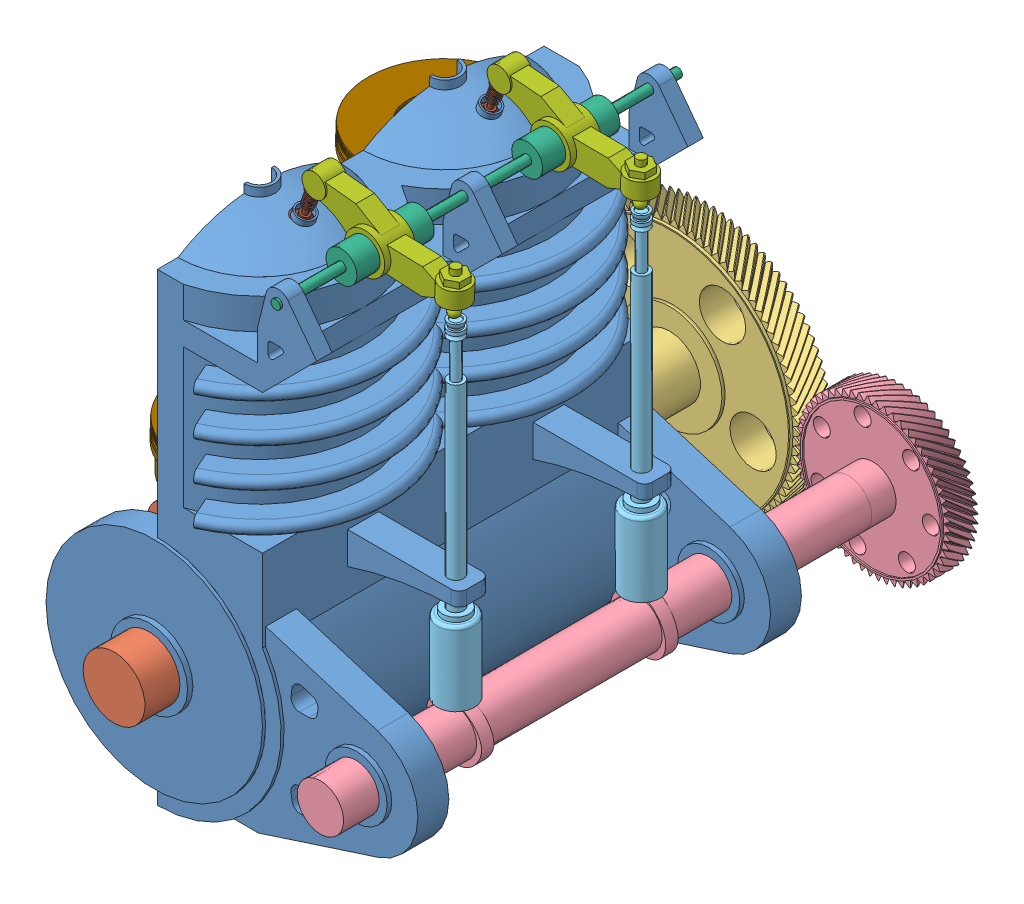
SolidWorks assembly Assem2, configuration Default. Lengths in mm.
Overall size (28.3 38.4 39.92).
18 component instances, 11 part files, 39 mates.
Components (placement in the parent):
- Two Cylinder Engine 1.Engine Block-1: Two Cylinder Engine 1.Engine Block [Default] at (0.0149 -0.0207 20.7725) size (23.65 32.82 28.05)
- Two Cylinder Engine 6...Crankshaft-1: Two Cylinder Engine 6...Crankshaft [Default] at (0.0149 7.9793 36.3725) x (-0.999999 0.00138 0) z (0 0 1) size (8.94 13 15.46)
- Two Cylinder Engine 6...Crankshaft-3: Two Cylinder Engine 6...Crankshaft [Default] at (0.0149 7.9793 29.8525) x (-0.999999 0.00138 0) z (0 0 -1) size (8.94 13 15.46)
- Two Cylinder Engine 8.Crankshaft Sprocket-1: Two Cylinder Engine 8.Crankshaft Sprocket [Default] at (0.0149 7.9793 12.6525) x (-0.999999 0.00138 0) z (0 0 1) size (16.49 16.5 9)
- Two Cylinder Engine 9.Camshaft with Sprocket-1: Two Cylinder Engine 9.Camshaft with Sprocket [Default] at (12.9589 7.5368 12.4525) x (-0.752432 0.65867 0) z (0 0 -1) size (10.07 10.06 38.02)
- Two Cylinder Engine 5..Pushrod-1: Two Cylinder Engine 5..Pushrod [Default] at (12.8149 13.9674 39.2725) x (-0.679929 0 -0.733278) z (0 1 0) size (2.4 2.4 21.18)
- Two Cylinder Engine 5..Pushrod-2: Two Cylinder Engine 5..Pushrod [Default] at (12.8149 14.0739 27.2725) x (0.936074 0 -0.351803) z (0 1 0) size (2.4 2.4 21.18)
- Two Cylinder Engine 10.Arbor-1: Two Cylinder Engine 10.Arbor [Default] at (7.8149 31.9993 45.9225) x (-0.655287 0.75538 0) z (0 0 -1) size (2 2 26)
- Two Cylinder Engine 7..Rocker Arm-1: Two Cylinder Engine 7..Rocker Arm [Default] at (7.8149 31.9993 39.1695) x (-0.800775 0.598966 0) z (0 0 -1) size (9.73 5.52 2)
- Two Cylinder Engine 7..Rocker Arm-2: Two Cylinder Engine 7..Rocker Arm [Default] at (7.8149 31.9993 27.1625) x (-0.813863 0.581056 0) z (0 0 -1) size (9.73 5.52 2)
- Two Cylinder Engine 4..Connecting Rod-1: Two Cylinder Engine 4..Connecting Rod [Default] at (0.0076 2.7203 39.1725) x (1 -0.00053 0) z (0 0 1) size (3.5 16.84 4)
- Two Cylinder Engine 4..Connecting Rod-2: Two Cylinder Engine 4..Connecting Rod [Default] at (0.0221 13.2383 27.0525) x (1 0.00053 0) z (0 0 1) size (3.5 16.84 4)
- Two Cylinder Engine 2.Pistonn-1: Two Cylinder Engine 2.Pistonn [Default] at (0.0149 15.5038 39.1825) x (0 0 1) z (-1 0 0) size (10 2.97 10)
- Two Cylinder Engine 3.Pin-1: Two Cylinder Engine 3.Pin [Default] at (0.0149 16.4103 34.4325) x (0.939236 0.343271 0) z (0 0 1) size (1.6 1.6 9.5)
- Two Cylinder Engine 2.Pistonn-2: Two Cylinder Engine 2.Pistonn [Default] at (0.0149 26.0218 27.1825) x (0 0 1) z (-1 0 0) size (10 2.97 10)
- Two Cylinder Engine 3.Pin-2: Two Cylinder Engine 3.Pin [Default] at (0.0149 26.9283 22.4325) x (0.999854 0.017111 0) z (0 0 1) size (1.6 1.6 9.5)
- Two Cylinder Engine 11.Valve-1: Two Cylinder Engine 11.Valve [Default] at (2.7613 30.7736 39.1825) x (0.939693 -0.34202 0) z (0 0 1) size (2.2 2.69 2.2)
- Two Cylinder Engine 11.Valve-2: Two Cylinder Engine 11.Valve [Default] at (2.7309 30.6901 27.1825) x (0.939693 -0.34202 0) z (0 0 1) size (2.2 2.69 2.2)
Mates (geometry in assembly coordinates):
- Concentric1: concentric: cylinder of Two Cylinder Engine 1.Engine Block-1 through (0.0149 7.9793 46.3125) axis (0 0 -1) radius 2; cylinder of Two Cylinder Engine 6...Crankshaft-1 through (0.0149 7.9793 45.2325) axis (0 0 -1) radius 2
- Distance1: distance = 2.6 mm: plane of Two Cylinder Engine 1.Engine Block-1 through (0.0149 7.9793 45.9725) normal (0 0 1); plane of Two Cylinder Engine 6...Crankshaft-1 through (0.0149 7.9793 48.5725) normal (0 0 1)
- Concentric2: concentric: cylinder of Two Cylinder Engine 1.Engine Block-1 through (0.0149 7.9793 21.8725) axis (0 0 -1) radius 2; cylinder of Two Cylinder Engine 6...Crankshaft-3 through (0.0149 7.9793 20.9925) axis (0 0 1) radius 2
- Parallel1: parallel: plane of Two Cylinder Engine 6...Crankshaft-1 through (-0.0886 5.4462 41.8725) normal (0.999999 -0.00138 0); plane of Two Cylinder Engine 6...Crankshaft-3 through (-0.0816 10.5127 24.3525) normal (0.999999 -0.00138 0)
- Coincident3: coincident: plane of Two Cylinder Engine 6...Crankshaft-1 through (0.0149 7.9793 33.1125) normal (0 0 -1); plane of Two Cylinder Engine 6...Crankshaft-3 through (0.0149 7.9793 33.1125) normal (0 0 1)
- Concentric3: concentric: cylinder of Two Cylinder Engine 6...Crankshaft-3 through (0.0149 7.9793 20.9925) axis (0 0 1) radius 2; cylinder of Two Cylinder Engine 8.Crankshaft Sprocket-1 through (0.0149 7.9793 17.6525) axis (0 0 -1) radius 2
- Parallel2: parallel: plane of Two Cylinder Engine 6...Crankshaft-3 through (-0.0816 10.5127 24.3525) normal (0.999999 -0.00138 0); plane of Two Cylinder Engine 8.Crankshaft Sprocket-1 through (0.2568 5.782 15.0525) normal (0.999999 -0.00138 0)
- Coincident5: coincident: plane of Two Cylinder Engine 6...Crankshaft-3 through (0.0149 7.9793 17.6525) normal (0 0 -1); plane of Two Cylinder Engine 8.Crankshaft Sprocket-1 through (0.0149 7.9793 17.6525) normal (0 0 1)
- Concentric4: concentric: cylinder of Two Cylinder Engine 1.Engine Block-1 through (12.9589 7.5368 45.8725) axis (0 0 -1) radius 1.5; cylinder of Two Cylinder Engine 9.Camshaft with Sprocket-1 through (12.9589 7.5368 18.3725) axis (0 0 -1) radius 1.5
- Distance2: distance = 2.6 mm: plane of Two Cylinder Engine 1.Engine Block-1 through (12.9589 7.5368 45.5725) normal (0 0 1); plane of Two Cylinder Engine 9.Camshaft with Sprocket-1 through (12.9589 7.5368 48.1725) normal (0 0 1)
- GearMate1: gear = 9.2099 : 15.559 mm: circle of Two Cylinder Engine 8.Crankshaft Sprocket-1; circle of Two Cylinder Engine 9.Camshaft with Sprocket-1
- Concentric7: concentric: cylinder of Two Cylinder Engine 1.Engine Block-1 through (12.8149 14.0793 39.2725) axis (0 1 0) radius 0.5; cylinder of Two Cylinder Engine 5..Pushrod-1 through (12.8149 29.4674 39.2725) axis (0 -1 0) radius 0.5
- Concentric8: concentric: cylinder of Two Cylinder Engine 1.Engine Block-1 through (12.8149 14.0793 27.2725) axis (0 1 0) radius 0.5; cylinder of Two Cylinder Engine 5..Pushrod-2 through (12.8149 29.5739 27.2725) axis (0 -1 0) radius 0.5
- CamMateTangent2: cam tangent: face of Two Cylinder Engine 9.Camshaft with Sprocket-1; plane of Two Cylinder Engine 5..Pushrod-1 through (12.8149 9.2174 39.2725) normal (0 -1 0)
- CamMateTangent3: cam tangent: face of Two Cylinder Engine 9.Camshaft with Sprocket-1; plane of Two Cylinder Engine 5..Pushrod-2 through (12.8149 9.3239 27.2725) normal (0 -1 0)
- Concentric9: concentric: cylinder of Two Cylinder Engine 1.Engine Block-1 through (7.8149 31.9993 45.7725) axis (0 0 -1) radius 0.3; cylinder of Two Cylinder Engine 10.Arbor-1 through (7.8149 31.9993 19.9225) axis (0 0 1) radius 0.3
- Distance4: distance = 0.15 mm: plane of Two Cylinder Engine 10.Arbor-1 through (7.8149 31.9993 45.9225) normal (0 0 1); plane of Two Cylinder Engine 1.Engine Block-1 through (0.0149 7.9793 45.7725) normal (0 0 1)
- Concentric10: concentric: cylinder of Two Cylinder Engine 10.Arbor-1 through (7.8149 31.9993 19.9225) axis (0 0 1) radius 0.3; cylinder of Two Cylinder Engine 7..Rocker Arm-1 through (7.8149 31.9993 38.1695) axis (0 0 1) radius 0.3
- Coincident10: coincident: plane of Two Cylinder Engine 10.Arbor-1 through (7.8149 31.9993 38.1695) normal (0 0 1); plane of Two Cylinder Engine 7..Rocker Arm-1 through (7.8149 31.9993 38.1695) normal (0 0 -1)
- Tangent1: tangent: plane of Two Cylinder Engine 5..Pushrod-1 through (12.8149 30.3074 39.2725) normal (0 1 0); sphere of Two Cylinder Engine 7..Rocker Arm-1
- Concentric11: concentric: cylinder of Two Cylinder Engine 10.Arbor-1 through (7.8149 31.9993 19.9225) axis (0 0 1) radius 0.3; cylinder of Two Cylinder Engine 7..Rocker Arm-2 through (7.8149 31.9993 26.1625) axis (0 0 1) radius 0.3
- Coincident11: coincident: plane of Two Cylinder Engine 10.Arbor-1 through (7.8149 31.9993 26.1625) normal (0 0 1); plane of Two Cylinder Engine 7..Rocker Arm-2 through (7.8149 31.9993 26.1625) normal (0 0 -1)
- Tangent2: tangent: plane of Two Cylinder Engine 5..Pushrod-2 through (12.8149 30.4139 27.2725) normal (0 1 0); sphere of Two Cylinder Engine 7..Rocker Arm-2
- Concentric12: concentric: cylinder of Two Cylinder Engine 6...Crankshaft-3 through (0.0221 13.2383 27.0525) axis (0 0 1) radius 1; cylinder of Two Cylinder Engine 4..Connecting Rod-2 through (0.0221 13.2383 27.5525) axis (0 0 -1) radius 1
- Coincident12: coincident: plane of Two Cylinder Engine 6...Crankshaft-3 through (-0.4374 12.8584 25.0525) normal (0 0 1); plane of Two Cylinder Engine 4..Connecting Rod-2 through (0.0221 13.2383 25.0525) normal (0 0 -1)
- Concentric13: concentric: cylinder of Two Cylinder Engine 6...Crankshaft-1 through (0.0076 2.7203 39.1725) axis (0 0 -1) radius 1; cylinder of Two Cylinder Engine 4..Connecting Rod-1 through (0.0076 2.7203 39.6725) axis (0 0 -1) radius 1
- Coincident13: coincident: plane of Two Cylinder Engine 6...Crankshaft-1 through (-0.4509 3.1015 41.1725) normal (0 0 -1); plane of Two Cylinder Engine 4..Connecting Rod-1 through (0.0076 2.7203 41.1725) normal (0 0 1)
- Concentric14: concentric: cylinder of Two Cylinder Engine 2.Pistonn-1 through (0.0149 16.4103 34.1825) axis (0 0 1) radius 0.8; cylinder of Two Cylinder Engine 3.Pin-1 through (0.0149 16.4103 43.9325) axis (0 0 -1) radius 0.8
- Width1: width: plane of Two Cylinder Engine 3.Pin-1 through (0.0149 16.4103 34.4325) normal (0 0 -1); plane of Two Cylinder Engine 3.Pin-1 through (0.0149 16.4103 43.9325) normal (0 0 1); plane of Two Cylinder Engine 2.Pistonn-1 through (-2.9351 17.5358 40.9325) normal (0 0 -1); plane of Two Cylinder Engine 2.Pistonn-1 through (-2.9351 17.5358 37.4325) normal (0 0 1)
- Concentric15: concentric: cylinder of Two Cylinder Engine 1.Engine Block-1 through (0.0149 7.9993 39.1825) axis (0 1 0) radius 5; cylinder of Two Cylinder Engine 2.Pistonn-1 through (0.0149 18.5038 39.1825) axis (0 1 0) radius 4.78
- Concentric16: concentric: cylinder of Two Cylinder Engine 4..Connecting Rod-1 through (0.0149 16.4103 39.6725) axis (0 0 -1) radius 0.8; cylinder of Two Cylinder Engine 3.Pin-1 through (0.0149 16.4103 43.9325) axis (0 0 -1) radius 0.8
- Concentric17: concentric: cylinder of Two Cylinder Engine 2.Pistonn-2 through (0.0149 26.9283 22.1825) axis (0 0 1) radius 0.8; cylinder of Two Cylinder Engine 3.Pin-2 through (0.0149 26.9283 31.9325) axis (0 0 -1) radius 0.8
- Width2: width: plane of Two Cylinder Engine 3.Pin-2 through (0.0149 26.9283 22.4325) normal (0 0 -1); plane of Two Cylinder Engine 3.Pin-2 through (0.0149 26.9283 31.9325) normal (0 0 1); plane of Two Cylinder Engine 2.Pistonn-2 through (-2.9351 28.0538 25.4325) normal (0 0 1); plane of Two Cylinder Engine 2.Pistonn-2 through (-2.9351 28.0538 28.9325) normal (0 0 -1)
- Concentric18: concentric: cylinder of Two Cylinder Engine 1.Engine Block-1 through (0.0149 7.9993 27.1825) axis (0 1 0) radius 5; cylinder of Two Cylinder Engine 2.Pistonn-2 through (0.0149 29.0218 27.1825) axis (0 1 0) radius 4.78
- Concentric19: concentric: cylinder of Two Cylinder Engine 4..Connecting Rod-2 through (0.0149 26.9283 27.5525) axis (0 0 -1) radius 0.8; cylinder of Two Cylinder Engine 3.Pin-2 through (0.0149 26.9283 31.9325) axis (0 0 -1) radius 0.8
- Concentric20: concentric: cylinder of Two Cylinder Engine 1.Engine Block-1 through (3.012 31.4625 39.1825) axis (-0.34202 -0.939693 0) radius 0.5; cylinder of Two Cylinder Engine 11.Valve-1 through (3.6813 33.3014 39.1825) axis (0.34202 0.939693 0) radius 0.4685
- Concentric21: concentric: cylinder of Two Cylinder Engine 1.Engine Block-1 through (3.012 31.4625 27.1825) axis (-0.34202 -0.939693 0) radius 0.5; cylinder of Two Cylinder Engine 11.Valve-2 through (3.6509 33.2178 27.1825) axis (0.34202 0.939693 0) radius 0.4685
- Tangent5: tangent: cylinder of Two Cylinder Engine 7..Rocker Arm-1 through (4.2287 33.8497 38.4695) axis (0 0 1) radius 0.7625; plane of Two Cylinder Engine 11.Valve-1 through (4.101 33.0848 39.1825) normal (0.34202 0.939693 0)
- Tangent6: tangent: cylinder of Two Cylinder Engine 7..Rocker Arm-2 through (4.1886 33.7697 26.4625) axis (0 0 1) radius 0.7625; plane of Two Cylinder Engine 11.Valve-2 through (4.0706 33.0012 27.1825) normal (0.34202 0.939693 0)
